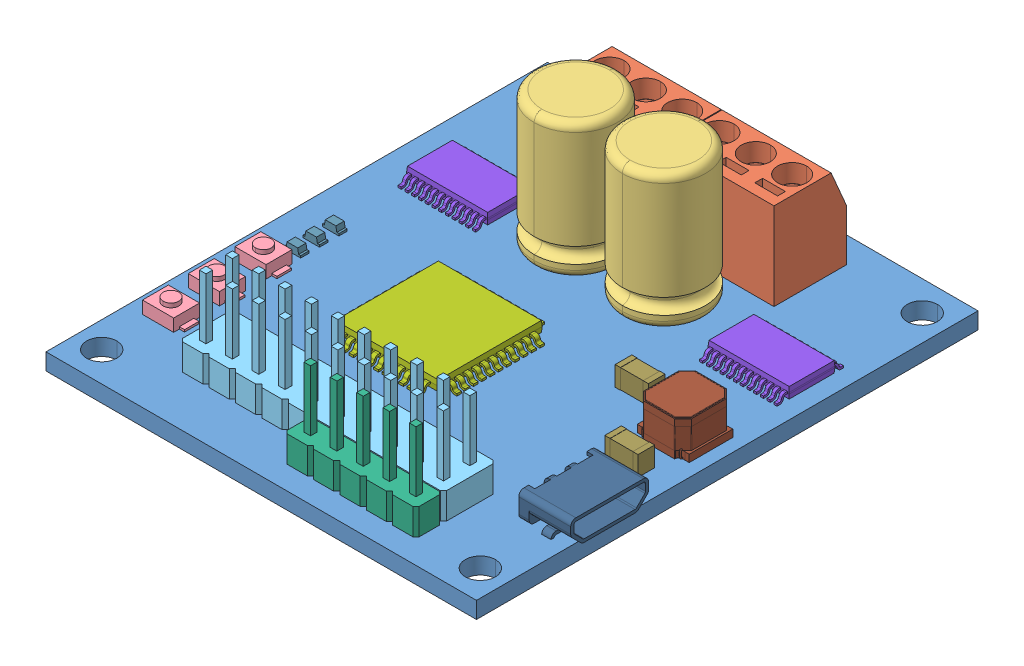
SolidWorks assembly motor-controller, configuration Default. Lengths in mm.
Overall size (117.5 56.01 87.66).
27 component instances, 14 part files, 0 mates.
Components (placement in the parent):
- MC7A_V5B.IGS-1: MC7A_V5B.IGS [Default] at origin size (117.5 56.01 87.66)
  - MC5A-PCB.IGS-2: MC5A-PCB.IGS [Default] at (90.9892 37.9455 60.0095) size (41.45 1.61 48.29)
  - ED2636-ND.IGS-3: ED2636-ND.IGS [Default] at (85.709 39.5455 41.8431) x (-1 0 0) z (0 0 -1) size (10.51 11.86 7.01)
  - ED2636-ND.IGS-4: ED2636-ND.IGS [Default] at (96.2918 39.5455 41.8431) x (-1 0 0) z (0 0 -1) size (10.51 11.86 7.01)
  - P15369TB-ND.IGS-3: P15369TB-ND.IGS [Default] at (95.395 39.5455 49.7941) x (-1 0 0) z (0 0 -1) size (13.01 16.01 8)
  - P15369TB-ND.IGS-4: P15369TB-ND.IGS [Default] at (86.9008 39.5455 49.7923) x (-1 0 0) z (0 0 -1) size (13.01 16.01 8)
  - SW1020CT-ND.IGS-4: SW1020CT-ND.IGS [Default] at (73.2925 39.5455 66.2406) x (-1 0 0) z (0 0 -1) size (4.01 1.61 2.51)
  - SW1020CT-ND.IGS-5: SW1020CT-ND.IGS [Default] at (73.2925 39.5455 70.7286) x (-1 0 0) z (0 0 -1) size (4.01 1.61 2.51)
  - SW1020CT-ND.IGS-6: SW1020CT-ND.IGS [Default] at (73.2925 39.5455 75.1362) x (-1 0 0) z (0 0 -1) size (4.01 1.61 2.51)
  - PBC10DAAN.IGS-2: PBC10DAAN.IGS [Default] at (79.5294 39.5455 76.739) size (25.41 11.44 5.09)
  - PBC05SAAN.IGS-2: PBC05SAAN.IGS [Default] at (92.2279 39.5455 80.6492) size (12.71 11.44 2.55)
  - ATXMEGA32A4U-AU-ND.IGS-2: ATXMEGA32A4U-AU-ND.IGS [Default] at (87.74 39.7455 63.8454) x (0 0 -1) z (1 0 0) size (12.01 1.21 12.01)
  - 620-1319-1-ND.IGS-3: 620-1319-1-ND.IGS [Default] at (106.2731 39.6955 50.308) size (7.81 1.21 6.41)
  - 620-1319-1-ND.IGS-4: 620-1319-1-ND.IGS [Default] at (77.2465 39.6955 50.308) size (7.81 1.21 6.41)
  - IRF7351TRPBFCT-ND.IGS-5: IRF7351TRPBFCT-ND.IGS [Default] at (76.1828 37.6966 49.2664) x (-1 0 0) z (0 0 1) size (5.01 1.76 6.21)
  - IRF7351TRPBFCT-ND.IGS-6: IRF7351TRPBFCT-ND.IGS [Default] at (81.9001 37.6966 49.2664) x (-1 0 0) z (0 0 1) size (5.01 1.76 6.21)
  - IRF7351TRPBFCT-ND.IGS-7: IRF7351TRPBFCT-ND.IGS [Default] at (99.7733 37.6966 49.2664) x (-1 0 0) z (0 0 1) size (5.01 1.76 6.21)
  - IRF7351TRPBFCT-ND.IGS-8: IRF7351TRPBFCT-ND.IGS [Default] at (105.4543 37.6966 49.2664) x (-1 0 0) z (0 0 1) size (5.01 1.76 6.21)
  - 609-4618-1-ND.IGS-2: 609-4618-1-ND.IGS [Default] at (112.2359 40.9455 71.8547) x (0 0 -1) z (1 0 0) size (7.51 3.08 5.02)
  - SRN5040-220MCT-ND.IGS-2: SRN5040-220MCT-ND.IGS [Default] at (105.6664 42.9455 62.8284) x (-1 0 0) z (0 0 1) size (5.06 4.03 5.12)
  - 587-3248-1-ND.IGS-3: 587-3248-1-ND.IGS [Default] at (102.2216 40.4955 58.909) x (0 0 -1) z (1 0 0) size (1.61 1.91 3.21)
  - 587-3248-1-ND.IGS-4: 587-3248-1-ND.IGS [Default] at (107.6317 40.4955 65.3191) x (0 0 -1) z (1 0 0) size (1.61 1.91 3.21)
  - DB2W40200LCT-ND.IGS-3: DB2W40200LCT-ND.IGS [Default] at (76.3453 37.9455 73.6091) x (0 0 1) z (1 0 0) size (3.51 0.81 1.61)
  - DB2W40200LCT-ND.IGS-4: DB2W40200LCT-ND.IGS [Default] at (74.2192 37.9455 73.6091) x (0 0 1) z (1 0 0) size (3.51 0.81 1.61)
  - 404-1004-1-ND.IGS-4: 404-1004-1-ND.IGS [Default] at (73.9119 39.5455 59.9969) size (1.61 0.71 0.81)
  - 404-1004-1-ND.IGS-5: 404-1004-1-ND.IGS [Default] at (73.9119 39.5455 61.8654) size (1.61 0.71 0.81)
  - 404-1004-1-ND.IGS-6: 404-1004-1-ND.IGS [Default] at (73.9119 39.5455 63.6743) size (1.61 0.71 0.81)
